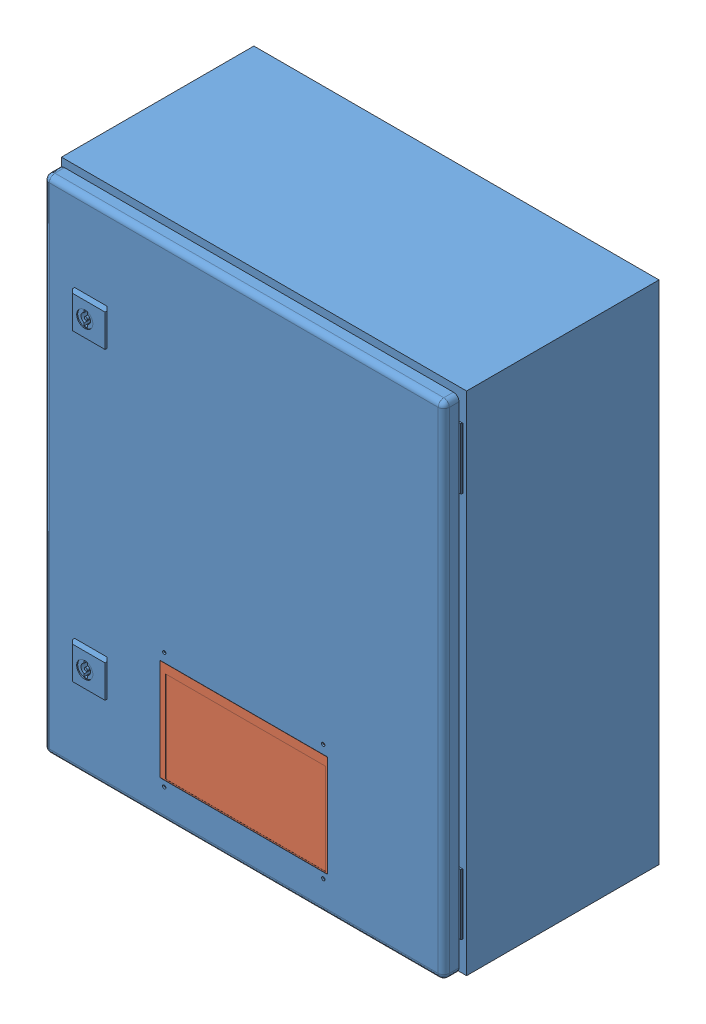
SolidWorks assembly Assem1, configuration Default. Lengths in mm.
Overall size (400 500 217).
2 component instances, 2 part files, 3 mates.
Components (placement in the parent):
- T00146-E00-R00-1: T00146-E00-R00 [Default] at (134.3363 96.2332 349.9354) size (400 500 217)
- T00169-E00-R00-1: T00169-E00-R00 [Default] at (134.3363 185.8832 451.5354) x (1 0 0) z (0 1 0) size (166 14.1 124.15)
Mates (geometry in assembly coordinates):
- Coincident1: coincident: plane of T00146-E00-R00-1 through (326.3363 588.2332 454.9354) normal (0 0 1); plane of T00169-E00-R00-1 through (299.9494 286.6238 454.9354) normal (0 0 1)
- Concentric1: concentric: circle of T00146-E00-R00-1; circle of T00169-E00-R00-1
- Concentric2: concentric: circle of T00146-E00-R00-1; circle of T00169-E00-R00-1
